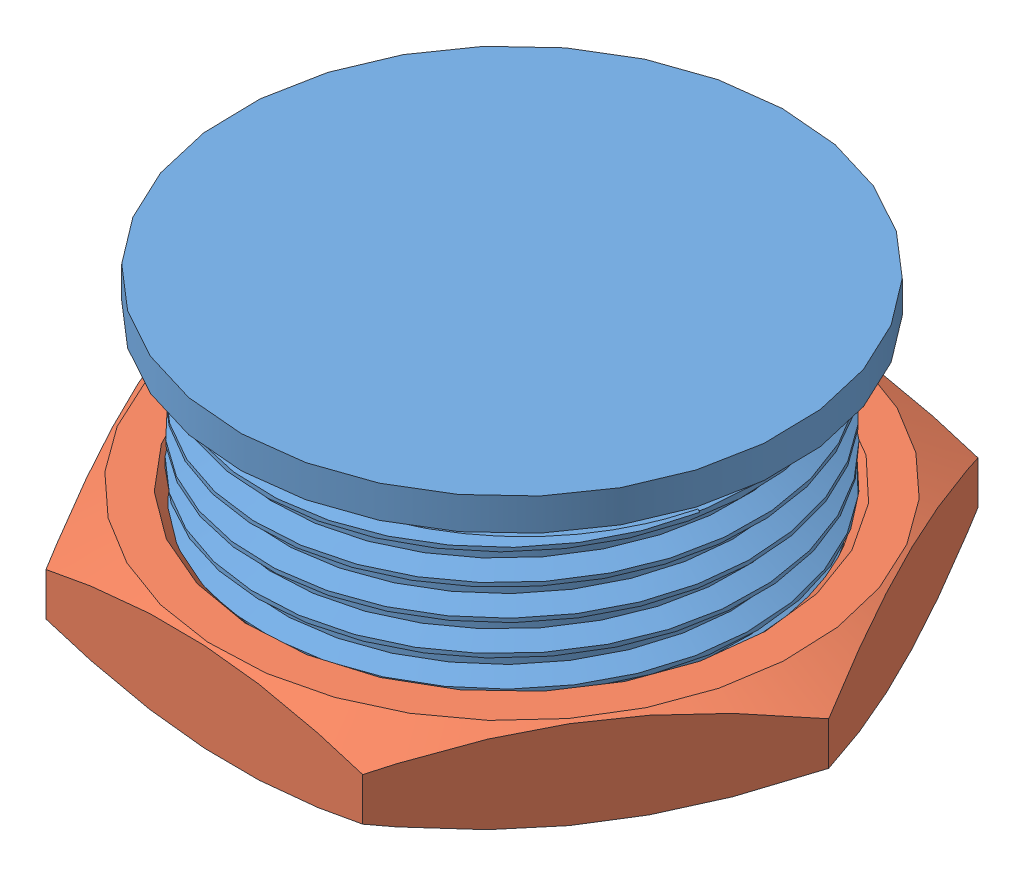
SolidWorks assembly кнопка, configuration По умолчанию. Lengths in mm.
Overall size (22.99 9.91 21.07).
3 component instances, 3 part files, 1 mates.
Components (placement in the parent):
- кнопка-корпус-1: кнопка-корпус [По умолчанию] x (-0.98212 0 -0.188257) z (0.188257 0 -0.98212) size (18 9.91 18)
- кнопка-гайка-1: кнопка-гайка [По умолчанию] at (0 0.4992 0) x (0.998361 0 0.05723) z (-0.05723 0 0.998361) size (21.94 3.24 19)
- кнопка-заливка-1: кнопка-заливка [По умолчанию] at (0 0.0462 0) size (14 7 14)
Mates (geometry in assembly coordinates):
- Совпадение2: coincident anti-aligned: plane of кнопка-корпус-1 through (0 7.0462 0) normal (0 -1 0); plane of кнопка-заливка-1 through (-7 7.0462 0) normal (0 1 0)
